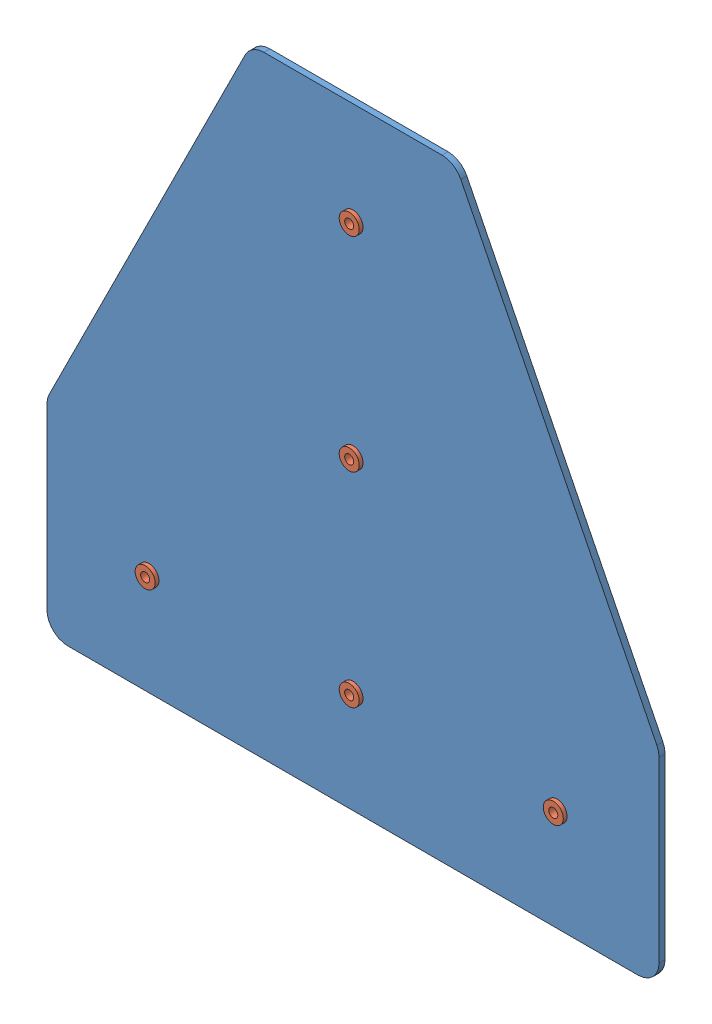
SolidWorks assembly T_w_rivets170927, configuration Default. Lengths in mm.
Overall size (161.93 161.92 7).
6 component instances, 2 part files, 10 mates.
Components (placement in the parent):
- 2inch_90degTee170927-1: 2inch_90degTee170927 [Default] at (38.352 -62.7849 -33.3812) size (161.93 161.93 1.59)
- 0.3125 rivet170927-1: 0.3125 rivet170927 [Default] at (-15.623 -35.7974 -31.7937) x (1 0 0) z (0 -1 0) size (5.3 7 5.3)
- 0.3125 rivet170927-2: 0.3125 rivet170927 [Default] at (38.352 -35.7974 -31.7937) x (0.987351 0.158553 0) z (0.158553 -0.987351 0) size (5.3 7 5.3)
- 0.3125 rivet170927-3: 0.3125 rivet170927 [Default] at (38.352 18.1776 -31.7937) x (0.959125 0.282984 0) z (0.282984 -0.959125 0) size (5.3 7 5.3)
- 0.3125 rivet170927-4: 0.3125 rivet170927 [Default] at (38.352 72.1526 -31.7937) x (0.928571 0.371154 0) z (0.371154 -0.928571 0) size (5.3 7 5.3)
- 0.3125 rivet170927-5: 0.3125 rivet170927 [Default] at (92.327 -35.7974 -31.7937) x (0.906989 0.421154 0) z (0.421154 -0.906989 0) size (5.3 7 5.3)
Mates (geometry in assembly coordinates):
- Coincident1: coincident anti-aligned: plane of 2inch_90degTee170927-1 through (-42.6105 -62.7849 -31.7937) normal (0 0 1); plane of 0.3125 rivet170927-1 through (-17.273 -35.7974 -31.7937) normal (0 0 -1)
- Concentric1: concentric anti-aligned: circle of 2inch_90degTee170927-1; circle of 0.3125 rivet170927-1
- Coincident2: coincident anti-aligned: plane of 2inch_90degTee170927-1 through (-42.6105 -62.7849 -31.7937) normal (0 0 1); plane of 0.3125 rivet170927-2 through (36.7229 -36.059 -31.7937) normal (0 0 -1)
- Concentric2: concentric anti-aligned: circle of 2inch_90degTee170927-1; circle of 0.3125 rivet170927-2
- Coincident3: coincident anti-aligned: plane of 2inch_90degTee170927-1 through (-42.6105 -62.7849 -31.7937) normal (0 0 1); plane of 0.3125 rivet170927-3 through (36.7695 17.7107 -31.7937) normal (0 0 -1)
- Concentric3: concentric aligned: circle of 2inch_90degTee170927-1; circle of 0.3125 rivet170927-3
- Coincident4: coincident anti-aligned: plane of 2inch_90degTee170927-1 through (-42.6105 -62.7849 -31.7937) normal (0 0 1); plane of 0.3125 rivet170927-4 through (36.8199 71.5402 -31.7937) normal (0 0 -1)
- Concentric4: concentric anti-aligned: circle of 2inch_90degTee170927-1; circle of 0.3125 rivet170927-4
- Coincident5: coincident anti-aligned: plane of 2inch_90degTee170927-1 through (-42.6105 -62.7849 -31.7937) normal (0 0 1); plane of 0.3125 rivet170927-5 through (90.8305 -36.4923 -31.7937) normal (0 0 -1)
- Concentric5: concentric anti-aligned: circle of 2inch_90degTee170927-1; circle of 0.3125 rivet170927-5
